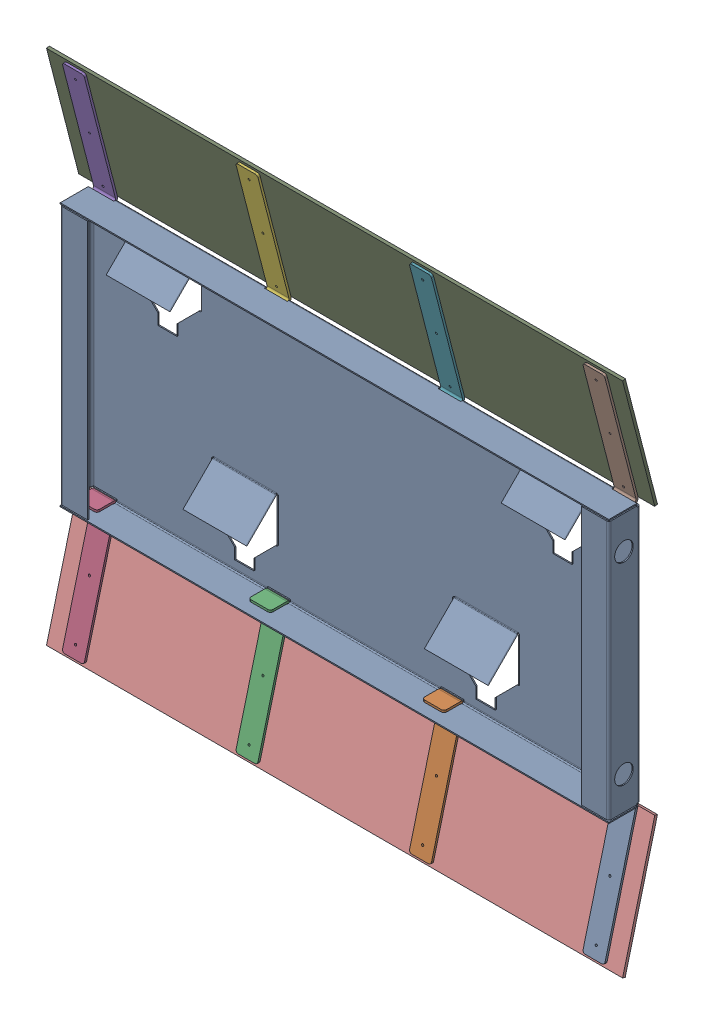
SolidWorks assembly GE-16013_ASM, configuration Default. Lengths in mm.
Overall size (1333.5 1200.11 83.95).
11 component instances, 3 part files, 0 mates.
Components (placement in the parent):
- GE-16010-1: GE-16010 [Default] at origin size (1270 609.6 73.03)
- GE-16012-1: GE-16012 [Default] at (602.4563 -297.1978 -1.6302) x (-1 0 0) z (0 0 1) size (50.8 295.12 78.11)
- GE-16012-2: GE-16012 [Default] at (200.8187 -297.1978 -1.6302) x (-1 0 0) z (0 0 1) size (50.8 295.12 78.11)
- GE-16012-3: GE-16012 [Default] at (-200.8187 -297.1978 -1.6302) x (-1 0 0) z (0 0 1) size (50.8 295.12 78.11)
- GE-16012-4: GE-16012 [Default] at (-602.4563 -297.1978 -1.6302) x (-1 0 0) z (0 0 1) size (50.8 295.12 78.11)
- GE-16012-5: GE-16012 [Default] at (-602.4563 297.1978 -1.6302) size (50.8 295.12 78.11)
- GE-16012-6: GE-16012 [Default] at (-200.8187 297.1978 -1.6302) size (50.8 295.12 78.11)
- GE-16012-7: GE-16012 [Default] at (200.8187 297.1978 -1.6302) size (50.8 295.12 78.11)
- GE-16012-8: GE-16012 [Default] at (602.4563 297.1978 -1.6302) size (50.8 295.12 78.11)
- GE-16011-1: GE-16011 [Default] at (0 450.9068 -38.1427) x (-1 0 0) z (0 -0.968246 -0.25) size (1333.5 6.35 298.45)
- GE-16011-2: GE-16011 [Default] at (0 -450.9068 -38.1427) x (1 0 0) z (0 0.968246 -0.25) size (1333.5 6.35 298.45)
